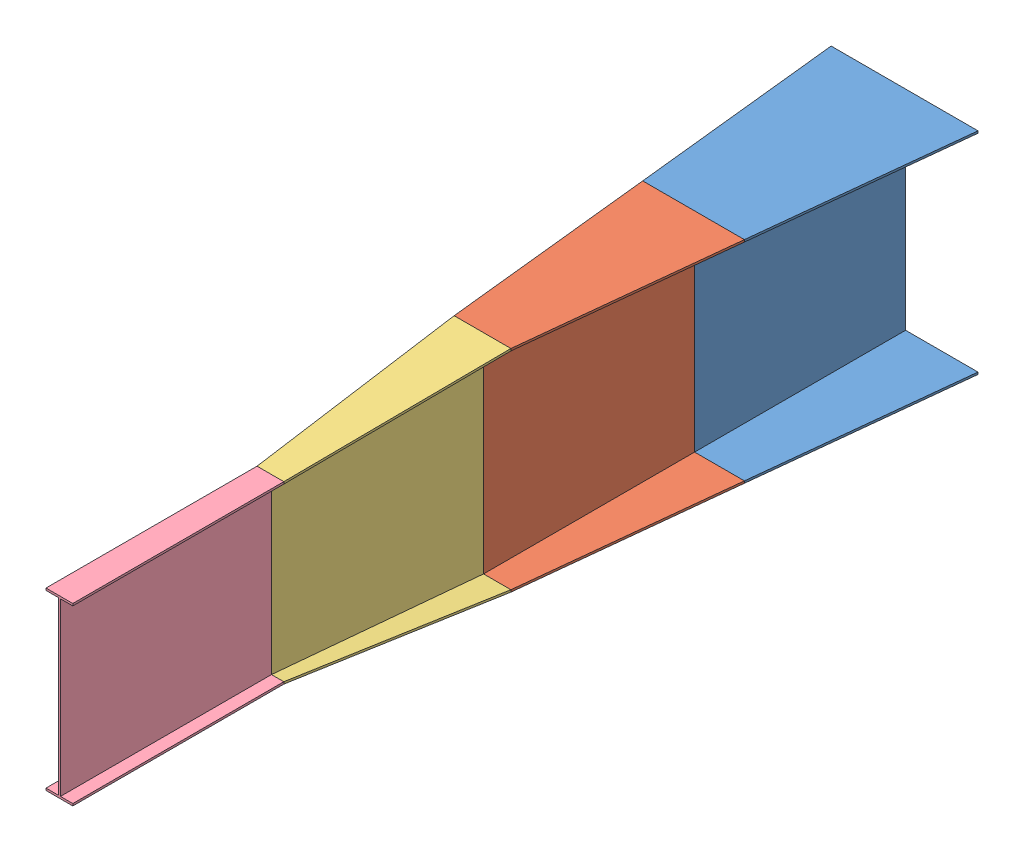
SolidWorks assembly 200kN assembly, configuration Default. Lengths in mm.
Overall size (696 1000 4000).
4 component instances, 4 part files, 8 mates.
Components (placement in the parent):
- 4m-3m-1: 4m-3m [Default] at (983.4156 374.3242 -289.3455) size (696 1000 1000)
- 3m-2m-1: 3m-2m [Default] at (983.4156 374.3242 710.6545) size (482 1000 1000)
- 2m-1m-1: 2m-1m [Default] at (983.4156 374.3242 1710.6545) size (269 1000 1000)
- 1m-0m-1: 1m-0m [Default] at (978.4156 458.8242 3710.6545) size (127 831 1000)
Mates (geometry in assembly coordinates):
- Coincident25: coincident: point of 4m-3m-1; point of 3m-2m-1
- Coincident26: coincident: point of 4m-3m-1; point of 3m-2m-1
- Coincident29: coincident: point of 3m-2m-1; point of 2m-1m-1
- Coincident30: coincident: point of 3m-2m-1; point of 2m-1m-1
- Coincident31: coincident: point of 3m-2m-1; point of 2m-1m-1
- Coincident32: coincident: line of 4m-3m-1 through (993.4156 1354.3242 710.6545) axis (1 0 0); point of 3m-2m-1
- Coincident33: coincident: line of 2m-1m-1 through (919.9156 448.8242 2710.6545) axis (1 0 0); line of 1m-0m-1 through (919.9156 448.8242 2710.6545) axis (1 0 0)
- Coincident34: coincident: point of 2m-1m-1; point of 1m-0m-1
